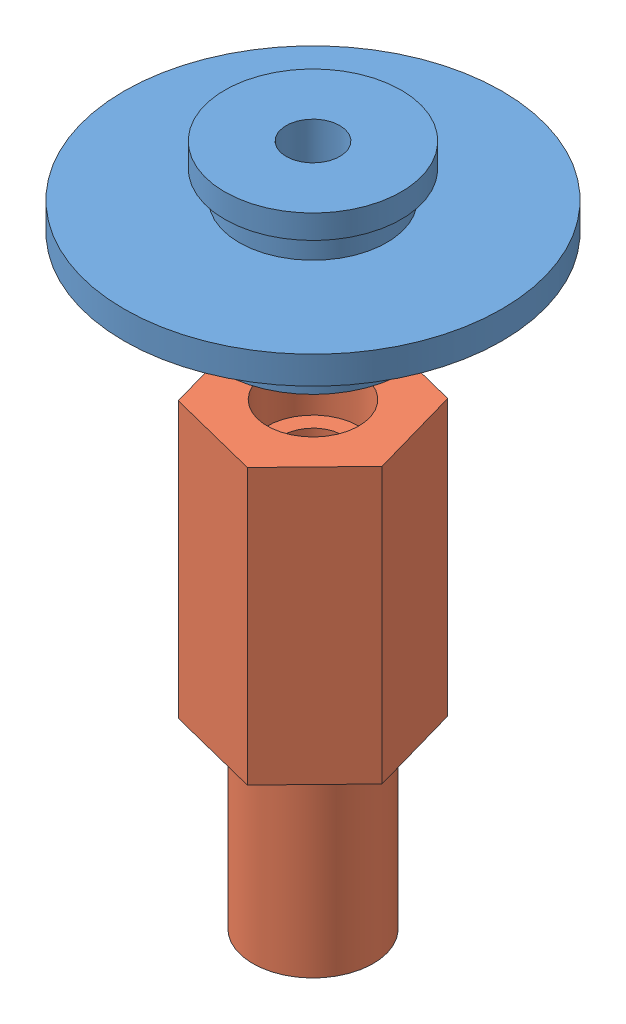
SolidWorks assembly ШтуцерВентСБ, configuration По умолчанию. Lengths in mm.
Overall size (41.2 74.43 41.2).
2 component instances, 2 part files, 3 mates.
Components (placement in the parent):
- ШтуцерВентильный1-1: ШтуцерВентильный1 [По умолчанию] at origin size (41.2 19.87 41.2)
- ШтуцерВрезьба-1: ШтуцерВрезьба [По умолчанию] at (0 -54.5551 0) x (0.962107 0 -0.272671) z (0.272671 0 0.962107) size (18 50 20.78)
Mates (geometry in assembly coordinates):
- Совпадение1: coordinate: point of ШтуцерВентильный1-1; point of assembly
- Концентричный1: concentric anti-aligned: cylinder of ШтуцерВентильный1-1 through (0 -11.4414 0) axis (0 -1 0) radius 5; cylinder of ШтуцерВрезьба-1 through (0 -9.5551 0) axis (0 1 0) radius 5
- Расстояние1: distance = 15.8278 mm anti-aligned: plane of ШтуцерВрезьба-1 through (0 -4.5551 0) normal (0 1 0); plane of ШтуцерВентильный1-1 through (20.6007 11.2727 0) normal (0 -1 0)
